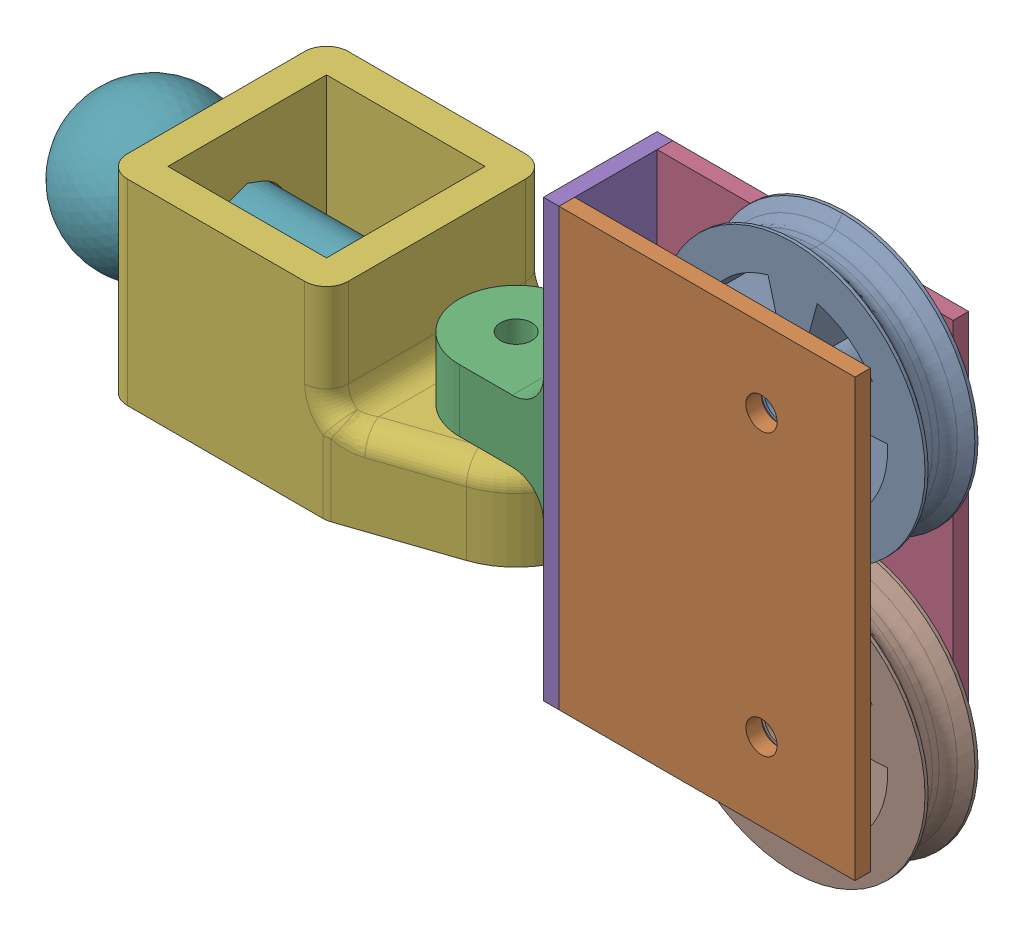
SolidWorks assembly Primary Pulley System, configuration Default. Lengths in mm.
Overall size (280.41 175 70.9).
5 component instances, 4 part files, 8 mates.
Components (placement in the parent):
- Primary Pulley Wheel-1: Primary Pulley Wheel [Default] at (-1360.39 93.3925 478.493) size (85 85 25)
- Pulley Mount-1: Pulley Mount [Default] at (-1430.39 38.3925 505.493) size (145.25 140 36.5)
- Rail Attachment-1: Rail Attachment [Default] at (-1543.74 10.8925 512.693) x (1 0 0) z (0 1 0) size (121.8 70.9 63)
- Rail Lock-1: Rail Lock [Default] at (-1548.5461 42.3925 499.393) size (110.46 48.63 48.63)
- Primary Pulley Wheel-2: Primary Pulley Wheel [Default] at (-1360.39 3.3925 478.493) size (85 85 25)
Mates (geometry in assembly coordinates):
- Concentric3: concentric anti-aligned: cylinder of Rail Attachment-1 through (-1444.901 42.3925 487.243) axis (-1 0 0) radius 13.2; cylinder of Rail Lock-1 through (-1487.84 42.3925 487.243) axis (1 0 0) radius 12.85
- Coincident1: coincident anti-aligned: plane of Rail Attachment-1 through (-1487.84 38.3925 512.693) normal (-1 0 0); plane of Rail Lock-1 through (-1487.84 42.3925 474.393) normal (1 0 0)
- Concentric4: concentric anti-aligned: cylinder of Pulley Mount-1 through (-1457.39 58.3925 487.243) axis (0 1 0) radius 5; cylinder of Rail Attachment-1 through (-1457.39 38.3925 487.243) axis (0 -1 0) radius 5.45
- Distance1: distance = 0 mm anti-aligned: plane of Pulley Mount-1 through (-1430.39 38.3925 505.493) normal (0 -1 0); plane of Rail Attachment-1 through (-1543.74 38.3925 512.693) normal (0 1 0)
- Concentric5: concentric aligned: cylinder of Primary Pulley Wheel-1 through (-1360.39 93.3925 478.493) axis (0 0 1) radius 5.1; cylinder of Pulley Mount-1 through (-1360.39 93.3925 505.493) axis (0 0 1) radius 5
- Distance2: distance = 1 mm anti-aligned: plane of Pulley Mount-1 through (-1430.39 58.3925 500.493) normal (0 0 -1); plane of Primary Pulley Wheel-1 through (-1360.39 93.3925 499.493) normal (0 0 1)
- Concentric6: concentric aligned: cylinder of Pulley Mount-1 through (-1360.39 3.3925 505.493) axis (0 0 1) radius 5; cylinder of Primary Pulley Wheel-2 through (-1360.39 3.3925 478.493) axis (0 0 1) radius 5.1
- Distance3: distance = 1 mm anti-aligned: plane of Pulley Mount-1 through (-1430.39 58.3925 500.493) normal (0 0 -1); plane of Primary Pulley Wheel-2 through (-1360.39 3.3925 499.493) normal (0 0 1)
